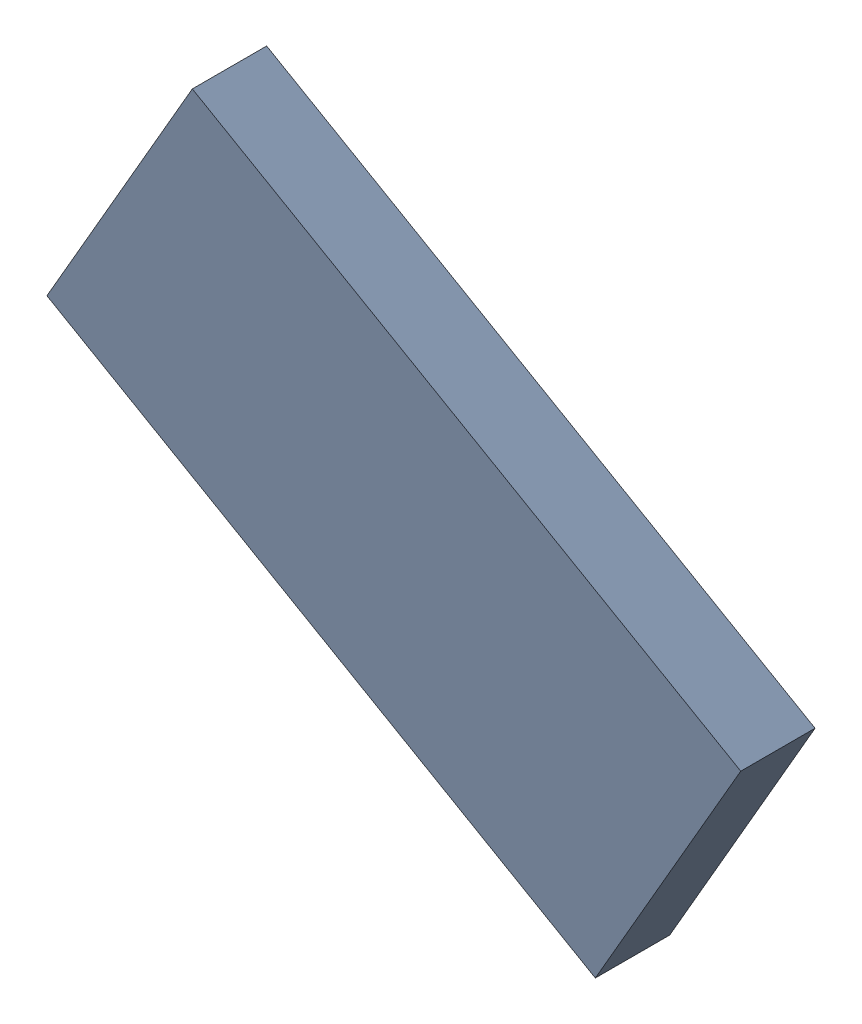
SolidWorks assembly TDA5340_TDA3, configuration Standard. Lengths in mm.
Overall size (10.74 8.8 1.15).
2 component instances, 1 part files, 0 mates.
Components (placement in the parent):
- 885544416-1: 885544416 [Standard] at (42.3622 -26.9179 0.05) size (10.74 8.8 1.15)
  - Extruded_11-1: Extruded_11 [Standard] at origin size (10.74 8.8 1.15)
